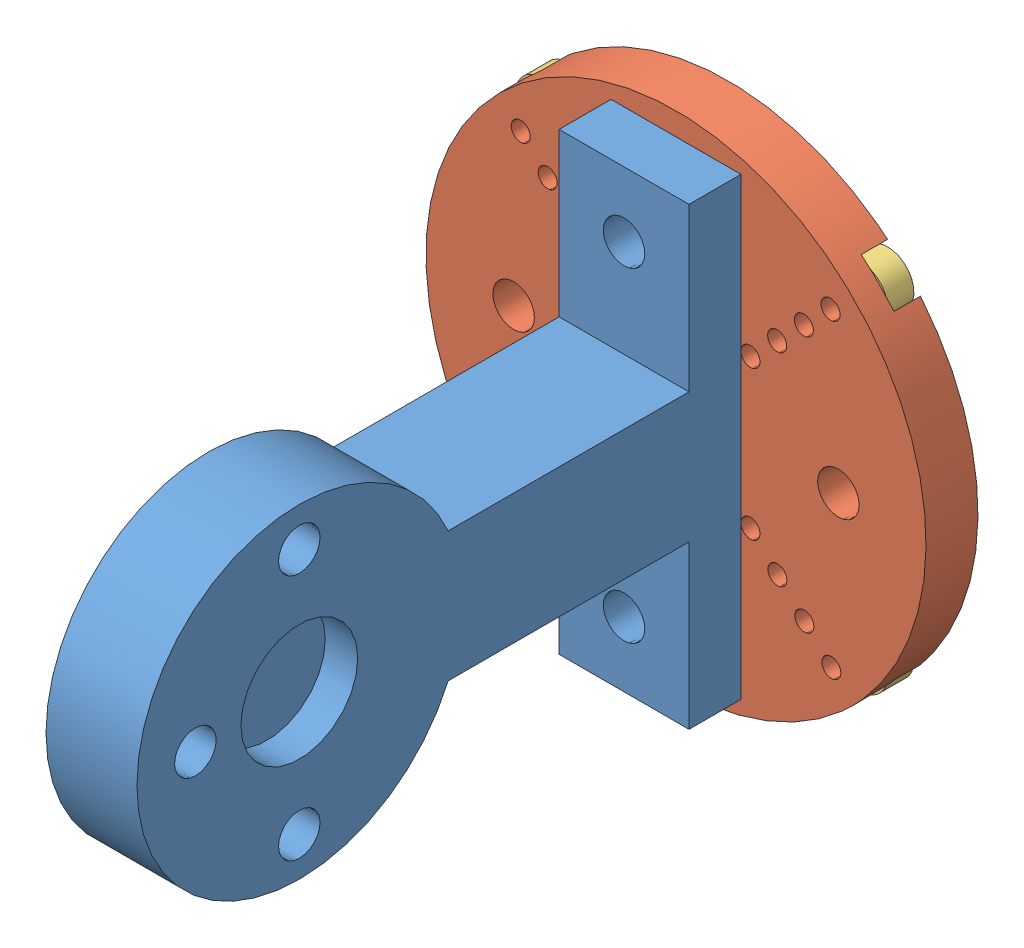
SolidWorks assembly FixationShaft_assembly, configuration Défaut. Lengths in mm.
Overall size (54.89 54.89 54.01).
4 component instances, 4 part files, 10 mates.
Components (placement in the parent):
- FixationShaft_up-1: FixationShaft_up [Défaut] at origin size (10 35 46.5)
- FixationShaft_bottom-1: FixationShaft_bottom [Défaut] at (0 0 -8) x (0.707107 -0.707107 0) z (0 0 1) size (38.5 38.5 4)
- Parallax-Servo-Horn.par-2: Parallax-Servo-Horn.par [Défaut] at (0 0 -5.968) x (0.707107 -0.707107 0) z (0 0 1) size (38.81 38.81 6.17)
- FixationShaft_bottom2-1: FixationShaft_bottom2 [Défaut] at (0 0 -9) x (0.707107 -0.707107 0) z (0 0 1) size (23.33 23.33 2)
Mates (geometry in assembly coordinates):
- Coincident1: coordinate: point of FixationShaft_up-1
- Angle1: planar angle = 0.785398 rad aligned: plane of FixationShaft_up-1 through (0 0 0) normal (0 1 0); plane of FixationShaft_bottom-1 through (0 0 -8) normal (0.707107 0.707107 0)
- Distance2: distance = 8 mm: point of FixationShaft_up-1; point of FixationShaft_bottom-1
- Coincident5: coincident anti-aligned: plane of FixationShaft_up-1 through (0 0 -4) normal (0 0 -1); plane of FixationShaft_bottom-1 through (0 0 -4) normal (0 0 1)
- Coincident9: coincident aligned: plane of FixationShaft_bottom-1 through (0 0 -8) normal (0 0 -1); plane of Parallax-Servo-Horn.par-2 through (8.9323 0 -8) normal (0 0 -1)
- Coincident7: coincident aligned: plane of FixationShaft_bottom-1 through (0 0 -8) normal (0.707107 0.707107 0); plane of Parallax-Servo-Horn.par-2 through (0 0 -5.968) normal (0.707107 0.707107 0)
- Coincident8: coincident aligned: plane of FixationShaft_bottom-1 through (0 0 -8) normal (0.707107 -0.707107 0); plane of Parallax-Servo-Horn.par-2 through (0 0 -5.968) normal (0.707107 -0.707107 0)
- Coincident10: coincident aligned: plane of FixationShaft_bottom-1 through (0 0 -8) normal (0.707107 0.707107 0); plane of FixationShaft_bottom2-1 through (0 0 -9) normal (0.707107 0.707107 0)
- Coincident11: coincident aligned: plane of FixationShaft_bottom-1 through (0 0 -8) normal (0.707107 -0.707107 0); plane of FixationShaft_bottom2-1 through (0 0 -9) normal (0.707107 -0.707107 0)
- Coincident12: coincident anti-aligned: plane of FixationShaft_bottom-1 through (0 0 -8) normal (0 0 -1); plane of FixationShaft_bottom2-1 through (0 0 -8) normal (0 0 1)
